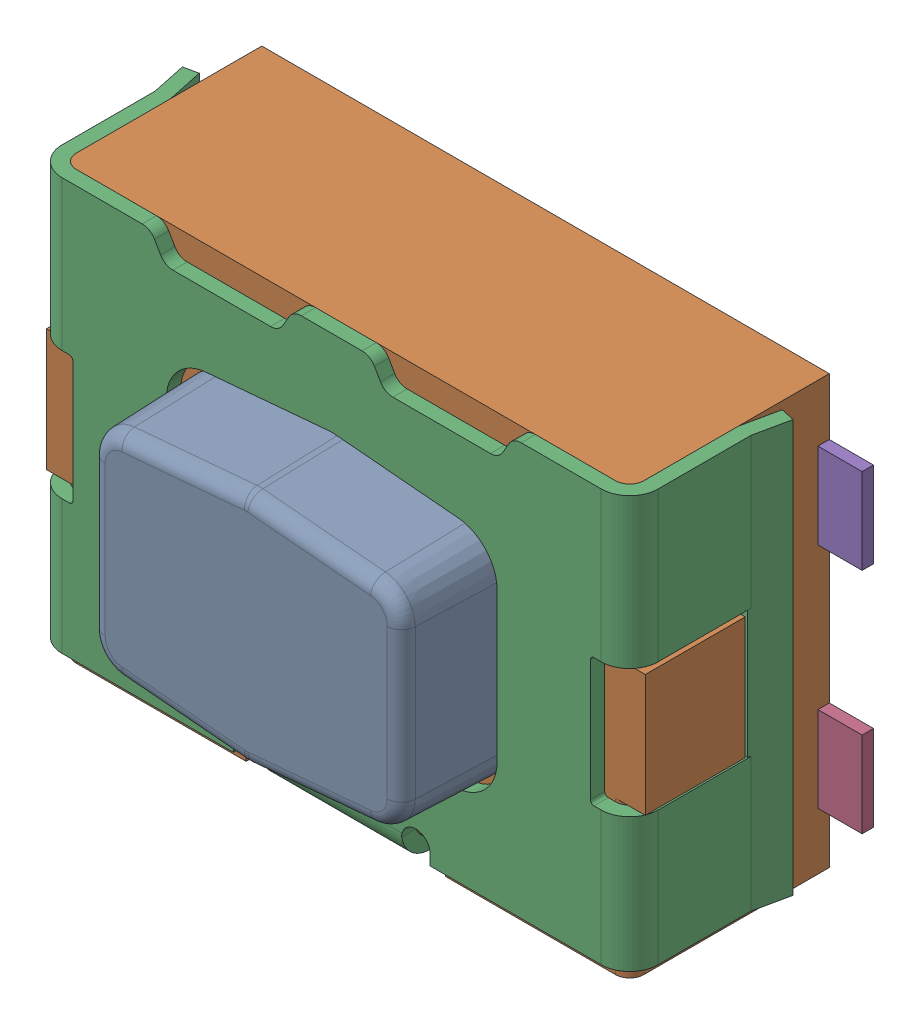
SolidWorks assembly SW201PCB, configuration Default. Lengths in mm.
Overall size (4.6 3 2.1).
5 component instances, 4 part files, 0 mates.
Components (placement in the parent):
- User_Library-Switch-CK-KMR2-1: User_Library-Switch-CK-KMR2 [Default] at (85.2 128.3999 0.0127) x (-1 0 0) z (0 0 1) size (4.6 3 2.1)
  - User_Library-Switch-CK-KMR2_Button-1: User_Library-Switch-CK-KMR2_Button [Default] at origin size (2.22 1.7 0.7)
  - User_Library-Switch-CK-KMR2_Boitier-1: User_Library-Switch-CK-KMR2_Boitier [Default] at origin size (4.2 3 1.4)
  - User_Library-Switch-CK-KMR2_Tole-1: User_Library-Switch-CK-KMR2_Tole [Default] at origin size (4.28 2.99 1.29)
  - User_Library-Switch-CK-KMR2_Pads-1: User_Library-Switch-CK-KMR2_Pads [Default] at origin size (4.6 2.2 0.08)
